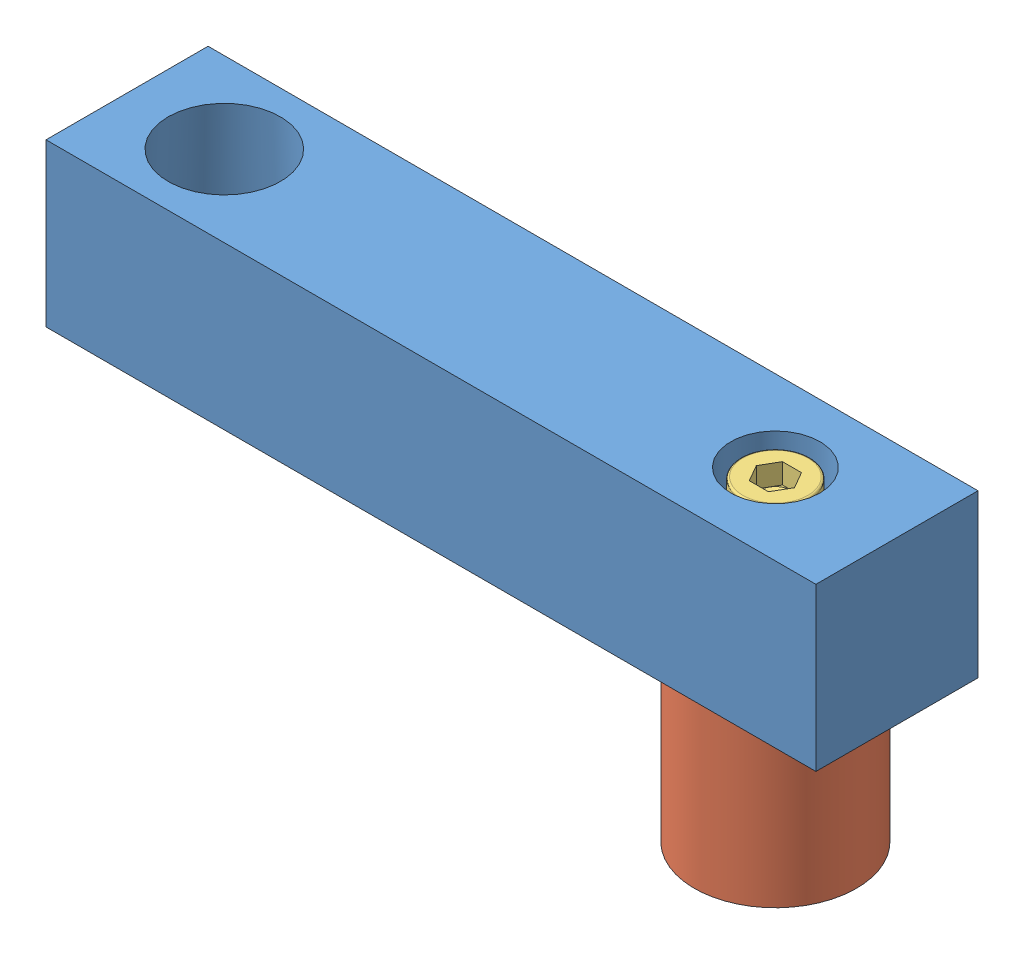
SolidWorks assembly assemb_braco_v3, configuration Default. Lengths in mm.
Overall size (95 40 26.14).
3 component instances, 3 part files, 4 mates.
Components (placement in the parent):
- clamping_arm_sp_v3-1: clamping_arm_sp_v3 [Default] at (-11.0842 57.292 80.6201) x (1 0 0) z (0 1 0) size (95 20 20)
- contact_end_full-1: contact_end_full [Default] at (56.9158 17.292 80.6201) x (-0.923645 0 -0.383249) z (0.383249 0 -0.923645) size (20 25 20)
- socket head cap screw_iso-2: socket head cap screw_iso [ISO 4762 M5 x 16 - 16N] at (56.9158 56.292 80.6201) x (0 -1 0) z (0 0 1) size (21 8.5 8.5)
Mates (geometry in assembly coordinates):
- Concentric1: concentric anti-aligned: cylinder of clamping_arm_sp_v3-1 through (56.9158 42.292 80.6201) axis (0 -1 0) radius 7.5; cylinder of contact_end_full-1 through (56.9158 37.292 80.6201) axis (0 1 0) radius 7.5
- Coincident1: coincident anti-aligned: plane of clamping_arm_sp_v3-1 through (56.9158 42.292 80.6201) normal (0 -1 0); plane of contact_end_full-1 through (56.9158 42.292 80.6201) normal (0 1 0)
- Concentric3: concentric anti-aligned: cylinder of clamping_arm_sp_v3-1 through (56.9158 57.292 80.6201) axis (0 -1 0) radius 2.75; cylinder of socket head cap screw_iso-2 through (56.9158 88.042 80.6201) axis (0 1 0) radius 4.25
- Coincident3: coincident anti-aligned: plane of clamping_arm_sp_v3-1 through (56.9158 51.292 80.6201) normal (0 1 0); plane of socket head cap screw_iso-2 through (61.1658 51.292 80.6201) normal (0 -1 0)
